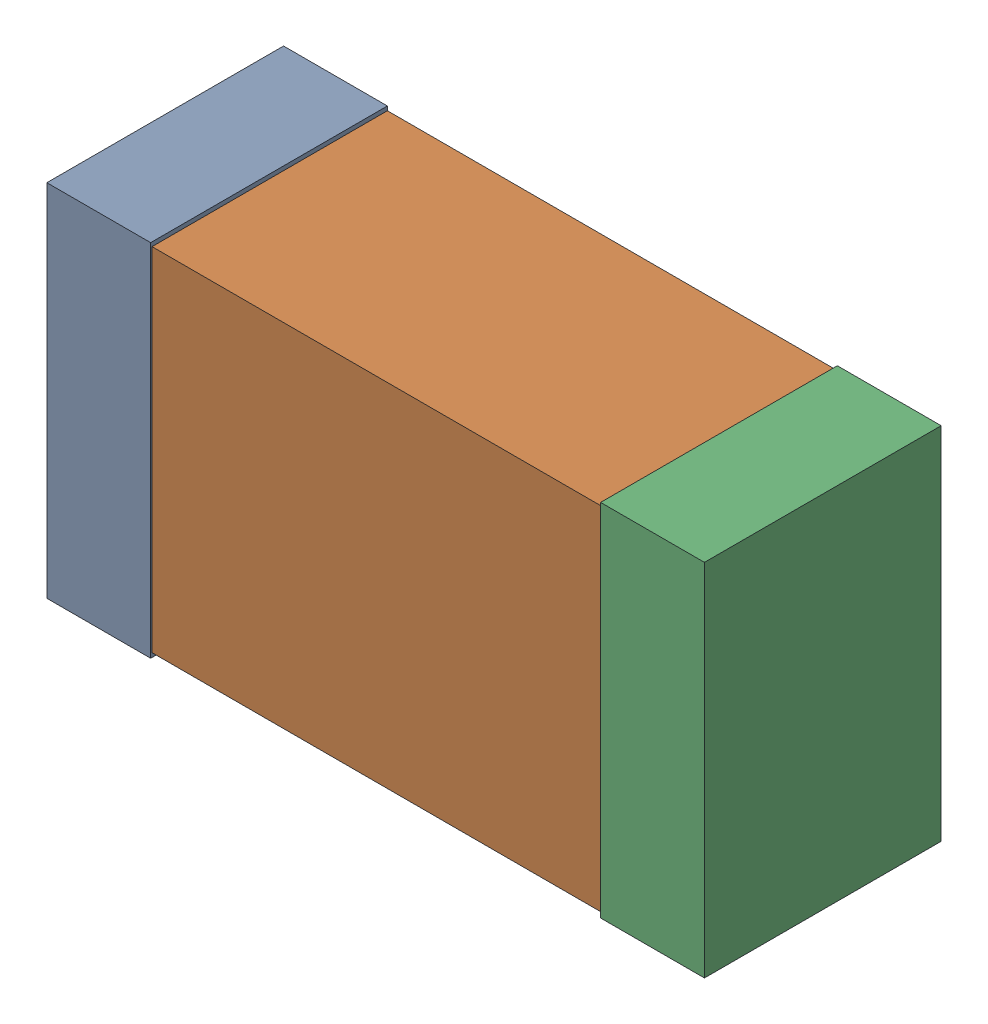
SolidWorks assembly C3Kanaloa_v2.0.0_Power, configuration Default. Lengths in mm.
Overall size (2.38 1.3 0.85).
6 component instances, 2 part files, 0 mates.
Components (placement in the parent):
- 352877648-1: 352877648 [Default] at (82.175 115.15 0) size (0.38 1.3 0.85)
  - Extruded_14-1: Extruded_14 [Default] at origin size (0.38 1.3 0.85)
- 352877904-1: 352877904 [Default] at (83.175 115.15 0) size (2.2 1.27 0.85)
  - Extruded_18-1: Extruded_18 [Default] at origin size (2.2 1.27 0.85)
- 352877648-2: 352877648 [Default] at (84.175 115.15 0) size (0.38 1.3 0.85)
  - Extruded_14-1: Extruded_14 [Default] at origin size (0.38 1.3 0.85)
